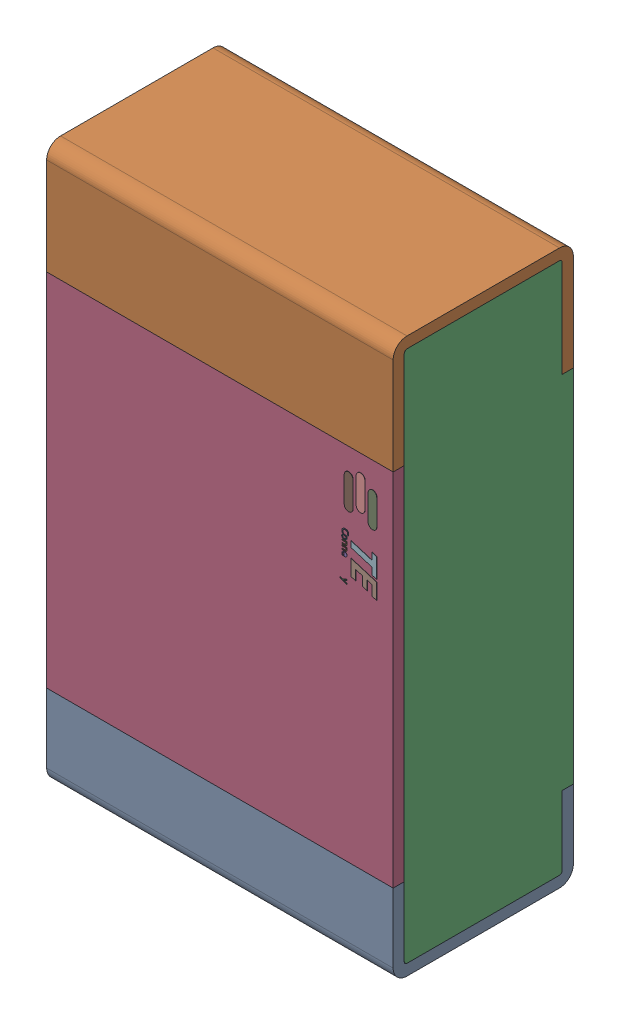
SolidWorks assembly R1.step, configuration Default. Lengths in mm.
Overall size (1.25 2 0.65).
5 component instances, 4 part files, 0 mates.
Components (placement in the parent):
- Res_TE_Connectivity_CPF0805B66R5E1_eec.step-1: Res_TE_Connectivity_CPF0805B66R5E1_eec.step [Default] at (7.366 38.862 0) x (0 -1 0) z (0 0 1) size (2 1.25 0.65)
  - 1.step-1: 1.step [Default] at origin size (2 1.25 0.65)
  - 2.step-1: 2.step [Default] at origin size (1.92 1.25 0.61)
  - 3.step-1: 3.step [Default] at origin size (1.3 1.25 0.04)
  - TE connectivity Logo 1 (2).step-1: TE connectivity Logo 1 (2).step [Default] at (5.4285 0.313 0.551) x (-1 0 0) z (0 0 1) size (0.37 0.13 0.11)
